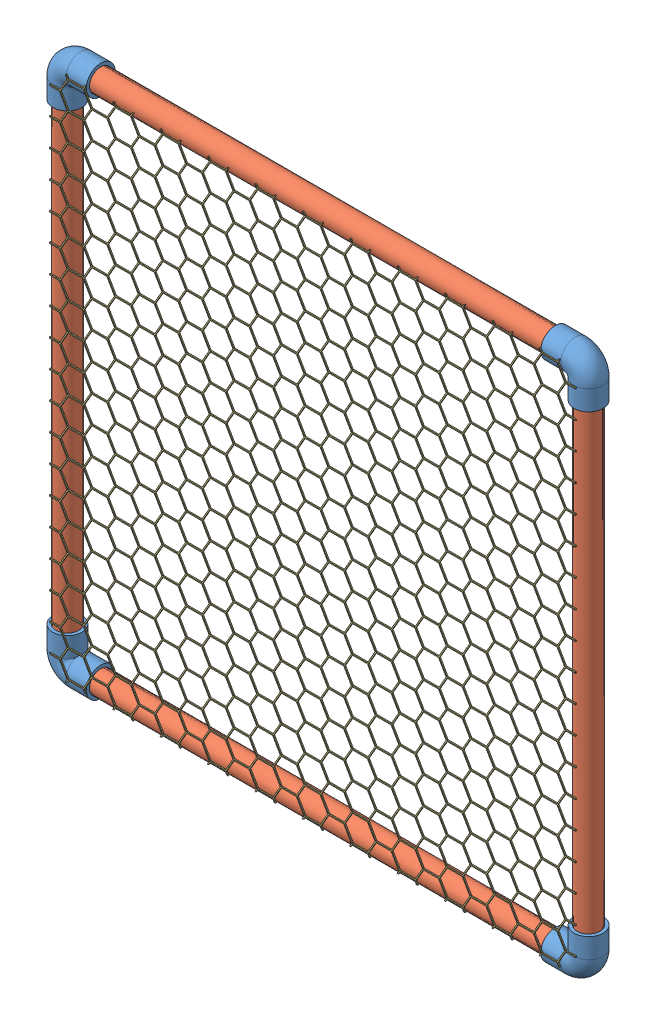
SolidWorks assembly ENVIRONMENTAL ELEVATOR, configuration Default. Lengths in mm.
Overall size (524.26 523.61 30.17).
9 component instances, 3 part files, 23 mates.
Components (placement in the parent):
- 1-2 PVC ELBOW-1: 1-2 PVC ELBOW [4880K21] at (-247.7 -247.7 0) x (-1 0 0) z (0 0 -1) size (45.53 45.53 27.56)
- 1-2 PVC ELBOW-2: 1-2 PVC ELBOW [4880K21] at (-247.7 247.7 0) x (0 1 0) z (0 0 -1) size (45.53 45.53 27.56)
- 1-2 PVC ELBOW-3: 1-2 PVC ELBOW [4880K21] at (247.7 247.7 0) x (0 1 0) z (0 0 1) size (45.53 45.53 27.56)
- 1-2 PVC ELBOW-4: 1-2 PVC ELBOW [4880K21] at (247.7 -247.7 0) size (45.53 45.53 27.56)
- 1-2 PVC PIPE 47CM-1: 1-2 PVC PIPE 47CM [48925K91] at (0 247.7 0) x (0 0 1) z (-1 0 0) size (21.34 21.34 470)
- 1-2 PVC PIPE 47CM-2: 1-2 PVC PIPE 47CM [48925K91] at (-247.7 0 0) x (0.717 0 0.697074) z (0 -1 0) size (21.34 21.34 470)
- 1-2 PVC PIPE 47CM-3: 1-2 PVC PIPE 47CM [48925K91] at (247.7 0 0) x (1 0 0) z (0 -1 0) size (21.34 21.34 470)
- 1-2 PVC PIPE 47CM-4: 1-2 PVC PIPE 47CM [48925K91] at (0 -247.7 0) x (0 0.47007 0.882629) z (-1 0 0) size (21.34 21.34 470)
- MESH A-1: MESH A [Default] at (0 0 14.7795) x (1 0 0) z (0 1 0) size (500 1 500)
Mates (geometry in assembly coordinates):
- Coincident1: coincident anti-aligned: plane of 1-2 PVC ELBOW-4 through (247.7 -235 0) normal (0 1 0); plane of 1-2 PVC PIPE 47CM-3 through (247.7 -235 0) normal (0 -1 0)
- Concentric1: concentric anti-aligned: cone of 1-2 PVC ELBOW-4 through (247.7 -215.95 0) axis (0 -1 0); cylinder of 1-2 PVC PIPE 47CM-3 through (247.7 -235 0) axis (0 1 0) radius 10.668
- Coincident2: coincident anti-aligned: plane of 1-2 PVC ELBOW-4 through (235 -247.7 0) normal (-1 0 0); plane of 1-2 PVC PIPE 47CM-4 through (235 -247.7 0) normal (1 0 0)
- Concentric2: concentric anti-aligned: cylinder of 1-2 PVC ELBOW-4 through (215.95 -247.7 0) axis (-1 0 0) radius 13.7795; cylinder of 1-2 PVC PIPE 47CM-4 through (-235 -247.7 0) axis (1 0 0) radius 10.668
- Coincident3: coincident anti-aligned: plane of 1-2 PVC ELBOW-3 through (247.7 235 0) normal (0 -1 0); plane of 1-2 PVC PIPE 47CM-3 through (247.7 235 0) normal (0 1 0)
- Concentric3: concentric anti-aligned: cylinder of 1-2 PVC ELBOW-3 through (247.7 215.95 0) axis (0 -1 0) radius 13.7795; cylinder of 1-2 PVC PIPE 47CM-3 through (247.7 -235 0) axis (0 1 0) radius 10.668
- Coincident4: coincident anti-aligned: plane of 1-2 PVC ELBOW-3 through (235 247.7 0) normal (-1 0 0); plane of 1-2 PVC PIPE 47CM-1 through (235 247.7 0) normal (1 0 0)
- Concentric4: concentric aligned: cylinder of 1-2 PVC ELBOW-3 through (247.7 247.7 0) axis (1 0 0) radius 13.7795; cylinder of 1-2 PVC PIPE 47CM-1 through (-235 247.7 0) axis (1 0 0) radius 10.668
- Coincident5: coincident anti-aligned: plane of 1-2 PVC ELBOW-2 through (-235 247.7 0) normal (1 0 0); plane of 1-2 PVC PIPE 47CM-1 through (-235 247.7 0) normal (-1 0 0)
- Concentric5: concentric anti-aligned: cylinder of 1-2 PVC ELBOW-2 through (-247.7 247.7 0) axis (-1 0 0) radius 13.7795; cylinder of 1-2 PVC PIPE 47CM-1 through (-235 247.7 0) axis (1 0 0) radius 10.668
- Coincident8: coincident anti-aligned: plane of 1-2 PVC ELBOW-1 through (-235 -247.7 0) normal (1 0 0); plane of 1-2 PVC PIPE 47CM-4 through (-235 -247.7 0) normal (-1 0 0)
- Concentric10: concentric anti-aligned: cone of 1-2 PVC ELBOW-1 through (-235 -247.7 0) axis (-1 0 0); cylinder of 1-2 PVC PIPE 47CM-4 through (-235 -247.7 0) axis (1 0 0) radius 10.668
- Coincident9: coincident anti-aligned: plane of 1-2 PVC ELBOW-1 through (-247.7 -235 0) normal (0 1 0); plane of 1-2 PVC PIPE 47CM-2 through (-247.7 -235 0) normal (0 -1 0)
- Concentric11: concentric anti-aligned: cylinder of 1-2 PVC ELBOW-1 through (-247.7 -247.7 0) axis (0 -1 0) radius 13.7795; cylinder of 1-2 PVC PIPE 47CM-2 through (-247.7 -235 0) axis (0 1 0) radius 10.668
- Concentric12: concentric anti-aligned: cylinder of 1-2 PVC ELBOW-1 through (-247.7 -247.7 0) axis (0 -1 0) radius 13.7795; cylinder of 1-2 PVC PIPE 47CM-2 through (-247.7 -235 0) axis (0 1 0) radius 10.668
- Concentric13: concentric aligned: cone of 1-2 PVC ELBOW-2 through (-247.7 235 0) axis (0 1 0); cylinder of 1-2 PVC PIPE 47CM-2 through (-247.7 -235 0) axis (0 1 0) radius 10.668
- Coincident12: coincident anti-aligned: plane of 1-2 PVC PIPE 47CM-2 through (-247.7 0 0) normal (0 -1 0); plane of assembly through (0 0 0) normal (0 1 0)
- Coincident13: coincident anti-aligned: plane of 1-2 PVC PIPE 47CM-1 through (0 247.7 0) normal (-1 0 0); plane of assembly through (0 0 0) normal (1 0 0)
- Coincident14: coincident aligned: plane of 1-2 PVC PIPE 47CM-1 through (0 247.7 0) normal (0 0 1); plane of assembly through (0 0 0) normal (0 0 1)
- Parallel1: parallel anti-aligned: plane of MESH A-1 through (0 0 14.7795) normal (0 0 -1); plane of assembly
- Tangent1: tangent anti-aligned: cylinder of 1-2 PVC ELBOW-2 through (-247.7 247.7 0) axis (-1 0 0) radius 13.7795; plane of MESH A-1 through (0 0 13.7795) normal (0 0 -1)
- Coincident16: coincident anti-aligned: plane of 1-2 PVC PIPE 47CM-3 through (247.7 0 0) normal (0 -1 0); plane of MESH A-1 through (0 0 14.7795) normal (0 1 0)
- Coincident17: coincident anti-aligned: plane of 1-2 PVC PIPE 47CM-1 through (0 247.7 0) normal (-1 0 0); plane of MESH A-1
